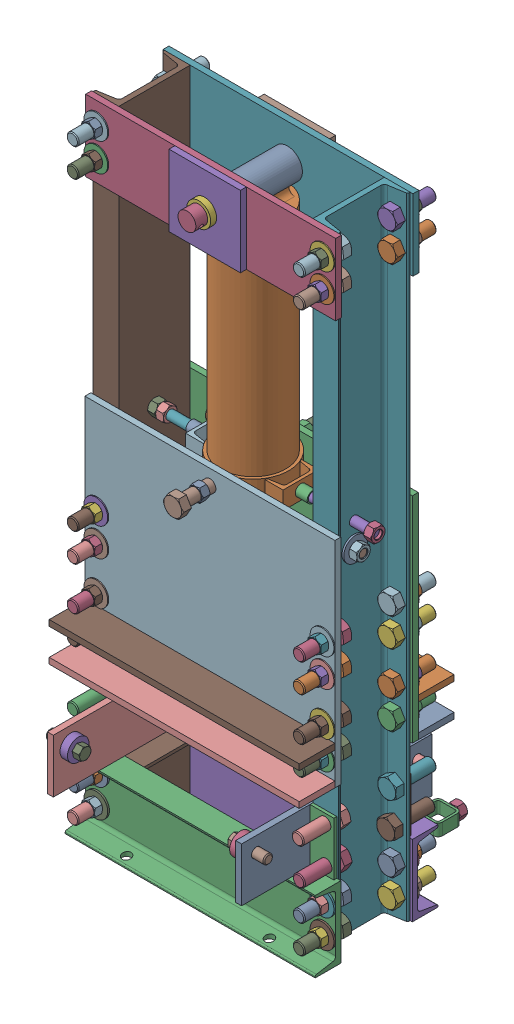
SolidWorks assembly 01-019-00-0_test, configuration Default. Lengths in mm.
Overall size (539.46 1346.2 428.04).
203 component instances, 34 part files, 0 mates.
Components (placement in the parent):
- 01-016-00-0-1: 01-016-00-0 [Default] at (0 -330.2 0) size (533.4 153.99 122.48)
  - 01-005-00-0-8-1: 01-005-00-0-8 [Default] at (-215.9 63.5 -27.3939) x (0 0 -1) z (0 1 0) size (67.69 50.8 28.57)
    - tube square_ai(PreviewCfg)-1: tube square_ai(PreviewCfg) [Default] at origin size (50.8 50.8 25.4)
    - hex nut_ai(HNUT 0.7500-10-D-C)-1: hex nut_ai(HNUT 0.7500-10-D-C) [Default] at (67.691 31.75 0) x (0 0 -1) z (1 0 0) size (28.57 33 16.89)
  - 01-005-00-0-9-1: 01-005-00-0-9 [Default] at (215.9 63.5 -27.3939) x (0 0 -1) z (0 -1 0) size (67.69 50.8 28.57)
    - tube square_ai(PreviewCfg)-1: tube square_ai(PreviewCfg) [Default] at origin size (50.8 50.8 25.4)
    - hex nut_ai(HNUT 0.7500-10-D-C)-1: hex nut_ai(HNUT 0.7500-10-D-C) [Default] at (67.691 31.75 0) x (0 0 -1) z (1 0 0) size (28.57 33 16.89)
  - 01-014-00-0-1: 01-014-00-0 [Default] at origin size (533.4 152.4 54.79)
- 01-116-00-0-1: 01-116-00-0 [Default] at (234.5817 266.7 103.5939) x (0 -1 0) z (-1 0 0) size (1346.2 152.4 109.58)
  - hex nut_ai(HNUT 0.7500-10-D-C)-1: hex nut_ai(HNUT 0.7500-10-D-C) [Default] at (-82.55 0 44.2849) size (28.57 33 16.89)
  - 01-115-00-0-1: 01-115-00-0 [Default] at origin size (1346.2 152.4 54.79)
  - 01-034-00-0-1: 01-034-00-0 [Default] at (177.8 0 54.7878) size (330.2 152.4 54.79)
- 01-114-00-0-1: 01-114-00-0 [Default] at (-234.5817 266.7 103.5939) x (0 -1 0) z (1 0 0) size (1346.2 152.4 109.58)
  - hex nut_ai(HNUT 0.7500-10-D-C)-1: hex nut_ai(HNUT 0.7500-10-D-C) [Default] at (-82.55 0 44.2849) size (28.57 33 16.89)
  - 01-034-00-0-1: 01-034-00-0 [Default] at (177.8 0 54.7878) size (330.2 152.4 54.79)
  - 01-015-00-0-1: 01-015-00-0 [Default] at origin size (1346.2 152.4 54.79)
- 01-039-00-0-1: 01-039-00-0 [Default] at (1.1707 831.85 101.4818) x (-1 0 0) z (0 0 1) size (254 946.15 152.4)
  - hex nut_ai(HNUT 0.7500-10-D-C)-1: hex nut_ai(HNUT 0.7500-10-D-C) [Default] at (-112.7125 840.359 -42.5511) x (1 0 0) z (0 -1 0) size (28.57 33 16.89)
  - PMC-21012-1: PMC-21012 [Default] at origin size (158.75 946.15 152.4)
  - 01-035-00-0-1: 01-035-00-0 [Default] at (-127 857.25 50.8) size (254 25.4 101.6)
  - 01-040-00-0-1: 01-040-00-0 [Default] at (57.15 831.85 -31.75) x (0 0 1) z (-1 0 0) size (63.5 25.4 25.4)
  - 01-040-00-0-2: 01-040-00-0 [Default] at (-57.15 831.85 31.75) x (0 0 -1) z (1 0 0) size (63.5 25.4 25.4)
  - 01-120-00-0-1: 01-120-00-0 [Default] at (-44.45 850.9 0) x (0 -1 0) z (0 0 1) size (38.1 88.9 38.1)
- 01-038-00-0-1: 01-038-00-0 [Default] at (-151.2293 -76.2 177.6818) size (304.8 82.55 152.4)
  - 01-036-00-0-1: 01-036-00-0 [Default] at origin size (304.8 25.4 152.4)
  - 01-037-00-0-1: 01-037-00-0 [Default] at (50.8 19.05 -76.2) size (19.05 63.5 19.05)
  - 01-037-00-0-2: 01-037-00-0 [Default] at (254 19.05 -76.2) size (19.05 63.5 19.05)
- 01-094-00-0-1: 01-094-00-0 [Default] at (133.1026 329.0672 91.7471) x (0 0 1) z (0 1 0) size (26.02 26.02 393.7)
  - 01-093-00-0-1: 01-093-00-0 [Default] at (-45.5164 -22.3944 39.2328) size (25.4 6.35 355.6)
  - TROD 0.7500-1x1.25-1: TROD 0.7500-1x1.25 [Default] at (-32.8164 -19.2194 -316.3672) x (0.5 -0.866025 0) z (0.866025 0.5 0) size (19.05 38.1 19.05)
- 01-113-00-0-1: 01-113-00-0 [Default] at (13.2518 299.9526 106.2418) x (1 0 0) z (0 1 0) size (63.45 76.2 38.1)
  - 01-112-00-0-1: 01-112-00-0 [Default] at (-117.0124 -34.5535 49.2974) size (38.05 76.2 38.1)
  - 01-111-00-0-1: 01-111-00-0 [Default] at (-142.4124 3.5465 49.2974) x (0 -1 0) z (0 0 1) size (23.81 25.4 23.81)
- 01-113-00-0-1-1: 01-113-00-0-1 [Default] at (-11.561 398.5474 107.4325) x (-1 0 0) z (0 -1 0) size (63.45 76.2 38.1)
  - 01-112-00-0-1: 01-112-00-0 [Default] at (-117.0124 -34.5535 49.2974) size (38.05 76.2 38.1)
  - 01-111-00-0-1: 01-111-00-0 [Default] at (-142.4124 3.5465 49.2974) x (0 -1 0) z (0 0 1) size (23.81 25.4 23.81)
- 01-117-00-0-1: 01-117-00-0 [Default] at (105.4514 349.25 103.5939) x (0 -1 0) z (0 0 1) size (28.57 165.1 33)
  - hex nut_ai(HNUT 0.7500-10-D-C)-1: hex nut_ai(HNUT 0.7500-10-D-C) [Default] at (0 165.1 0) x (1 0 0) z (0 1 0) size (28.57 33 16.89)
  - TROD 0.7500-1x6.25-1: TROD 0.7500-1x6.25 [Default] at origin size (19.05 158.75 19.05)
- 01-117-00-0-1-1: 01-117-00-0-1 [Default] at (-103.7607 349.25 103.5939) x (0 1 0) z (0 0 1) size (28.57 165.1 33)
  - hex nut_ai(HNUT 0.7500-10-D-C)-1: hex nut_ai(HNUT 0.7500-10-D-C) [Default] at (0 165.1 0) x (1 0 0) z (0 1 0) size (28.57 33 16.89)
  - TROD 0.7500-1x6.25-1: TROD 0.7500-1x6.25 [Default] at origin size (19.05 158.75 19.05)
- 01-097-00-0-1: 01-097-00-0 [Default] at (237.3376 298.45 103.5939) x (0 -0.797124 0.603815) z (0 -0.603815 -0.797124) size (141.46 99.52 78.97)
  - TROD 0.7500-1x3.5-1: TROD 0.7500-1x3.5 [Default] at origin size (19.05 88.9 19.05)
  - 01-096-00-0-1: 01-096-00-0 [Default] at (-127.635 93.6625 -64.2073) x (0.119593 0.96382 -0.238218) z (0.432432 -0.266552 -0.861367) size (9.53 152.4 9.53)
- Cam_Support_Ass-1: Cam_Support_Ass [Default] at (-231.8482 -246.6552 110.6361) x (0 0 -1) z (0 1 0) size (406.4 63.5 114.3)
  - 01-020-00-0-1: 01-020-00-0 [Default] at (-221.5578 -37.3604 106.9552) size (406.4 12.7 114.3)
  - Cam Support Tab-1: Cam Support Tab [Default] at (83.2422 -24.6604 106.9552) x (0 1 0) z (-1 0 0) size (50.8 114.3 6.35)
  - Cam Support Tab-2: Cam Support Tab [Default] at (-75.5078 -24.6604 106.9552) x (0 1 0) z (-1 0 0) size (50.8 114.3 6.35)
- Cam_Support_Ass_3-1: Cam_Support_Ass_3 [Default] at (205.4753 -251.743 123.9765) x (0 0 1) z (0 1 0) size (406.4 63.5 114.3)
  - 01-020-00-0-1: 01-020-00-0 [Default] at (-198.1826 -10.9875 112.043) size (406.4 12.7 114.3)
  - Cam Support Tab-1: Cam Support Tab [Default] at (-102.9326 1.7125 112.043) x (0 1 0) z (-1 0 0) size (50.8 114.3 6.35)
  - Cam Support Tab-2: Cam Support Tab [Default] at (55.8174 1.7125 112.043) x (0 1 0) z (-1 0 0) size (50.8 114.3 6.35)
- Base Plate Ass-1: Base Plate Ass [Default] at (51.7384 868.2539 156.4809) size (533.4 152.4 38.1)
  - Base plate update-1: Base plate update [Default] at (-316.9216 -80.8539 23.313) size (533.4 152.4 12.7)
  - Base Plate Support-1: Base Plate Support [Default] at (-126.4216 -80.8539 36.013) size (152.4 152.4 12.7)
  - 01-109-00-0-1: 01-109-00-0 [Default] at (-50.2216 -4.6539 23.313) x (1 0 0) z (0 -1 0) size (50.8 38.1 50.8)
- Base Plate Ass-1-1: Base Plate Ass-1 [Default] at (-48.7992 868.2539 50.7069) x (-1 0 0) z (0 0 -1) size (533.4 152.4 38.1)
  - Base plate update-1: Base plate update [Default] at (-316.9216 -80.8539 23.313) size (533.4 152.4 12.7)
  - Base Plate Support-1: Base Plate Support [Default] at (-126.4216 -80.8539 36.013) size (152.4 152.4 12.7)
  - 01-109-00-0-1: 01-109-00-0 [Default] at (-50.2216 -4.6539 23.313) x (1 0 0) z (0 -1 0) size (50.8 38.1 50.8)
- chamber wall ass-1: chamber wall ass [Default] at (-124.178 118.8769 136.5221) x (-1 0 0) z (0 0 1) size (533.4 457.2 88.9)
  - Chamber wall flange-1: Chamber wall flange [Default] at (-328.7125 182.3769 97.008) size (533.4 12.7 76.2)
  - Chamber wall flange-2: Chamber wall flange [Default] at (-328.7125 112.5269 97.008) size (533.4 12.7 76.2)
  - Chamber Walls-1: Chamber Walls [Default] at (-390.878 195.0769 43.2718) size (533.4 457.2 12.7)
- chamber wall ass-1-1: chamber wall ass-1 [Default] at (124.178 118.8769 70.6657) x (1 0 0) z (0 0 -1) size (533.4 457.2 88.9)
  - Chamber wall flange-1: Chamber wall flange [Default] at (-328.7125 182.3769 97.008) size (533.4 12.7 76.2)
  - Chamber wall flange-2: Chamber wall flange [Default] at (-328.7125 112.5269 97.008) size (533.4 12.7 76.2)
  - Chamber Walls-1: Chamber Walls [Default] at (-390.878 195.0769 43.2718) size (533.4 457.2 12.7)
- hex nut_ai(HNUT 0.7500-10-D-C)-1: hex nut_ai(HNUT 0.7500-10-D-C) [Default] at (-241.3 30.1625 12.5315) x (-0.923728 0.383049 0) z (0 0 1) size (28.57 33 16.89)
- hex nut_ai(HNUT 0.7500-10-D-C)-2: hex nut_ai(HNUT 0.7500-10-D-C) [Default] at (241.3 833.4375 211.5439) size (28.57 33 16.89)
- hex nut_ai(HNUT 0.7500-10-D-C)-3: hex nut_ai(HNUT 0.7500-10-D-C) [Default] at (241.3 -360.3625 211.5439) size (28.57 33 16.89)
- hex nut_ai(HNUT 0.7500-10-D-C)-4: hex nut_ai(HNUT 0.7500-10-D-C) [Default] at (173.4058 349.25 103.5939) x (0 0 1) z (-1 0 0) size (28.57 33 16.89)
- hex nut_ai(HNUT 0.7500-10-D-C)-5: hex nut_ai(HNUT 0.7500-10-D-C) [Default] at (-241.3 -30.1625 194.6563) x (-1 0 0) z (0 0 -1) size (28.57 33 16.89)
- hex nut_ai(HNUT 0.7500-10-D-C)-6: hex nut_ai(HNUT 0.7500-10-D-C) [Default] at (241.3 893.7625 211.5439) size (28.57 33 16.89)
- hex nut_ai(HNUT 0.7500-10-D-C)-7: hex nut_ai(HNUT 0.7500-10-D-C) [Default] at (241.3 -300.0375 211.5439) size (28.57 33 16.89)
- hex nut_ai(HNUT 0.7500-10-D-C)-8: hex nut_ai(HNUT 0.7500-10-D-C) [Default] at (-241.3 30.1625 194.6563) x (-1 0 0) z (0 0 -1) size (28.57 33 16.89)
- hex nut_ai(HNUT 0.7500-10-D-C)-9: hex nut_ai(HNUT 0.7500-10-D-C) [Default] at (241.3 122.2375 -4.3561) x (0.923728 0.383049 0) z (0 0 -1) size (28.57 33 16.89)
- hex nut_ai(HNUT 0.7500-10-D-C)-10: hex nut_ai(HNUT 0.7500-10-D-C) [Default] at (0 349.25 207.0227) x (0 1 0) z (0 0 -1) size (28.57 33 16.89)
- hex nut_ai(HNUT 0.7500-10-D-C)-11: hex nut_ai(HNUT 0.7500-10-D-C) [Default] at (241.3 182.5625 -4.3561) x (0.923728 0.383049 0) z (0 0 -1) size (28.57 33 16.89)
- hex nut_ai(HNUT 0.7500-10-D-C)-12: hex nut_ai(HNUT 0.7500-10-D-C) [Default] at (0 349.25 0.1651) x (0.924225 -0.381849 0) z (0 0 1) size (28.57 33 16.89)
- hex nut_ai(HNUT 0.7500-10-D-C)-13: hex nut_ai(HNUT 0.7500-10-D-C) [Default] at (-241.3 122.2375 194.6563) x (-1 0 0) z (0 0 -1) size (28.57 33 16.89)
- hex nut_ai(HNUT 0.7500-10-D-C)-14: hex nut_ai(HNUT 0.7500-10-D-C) [Default] at (-100.4293 -8.509 101.4818) x (1 0 0) z (0 1 0) size (28.57 33 16.89)
- hex nut_ai(HNUT 0.7500-10-D-C)-15: hex nut_ai(HNUT 0.7500-10-D-C) [Default] at (-241.3 182.5625 194.6563) x (-1 0 0) z (0 0 -1) size (28.57 33 16.89)
- hex nut_ai(HNUT 0.7500-10-D-C)-16: hex nut_ai(HNUT 0.7500-10-D-C) [Default] at (-241.3 -360.3625 -4.3527) x (-1 0 0) z (0 0 -1) size (28.57 33 16.89)
- hex nut_ai(HNUT 0.7500-10-D-C)-17: hex nut_ai(HNUT 0.7500-10-D-C) [Default] at (241.3 833.4375 -4.3561) x (0.923728 0.383049 0) z (0 0 -1) size (28.57 33 16.89)
- hex nut_ai(HNUT 0.7500-10-D-C)-18: hex nut_ai(HNUT 0.7500-10-D-C) [Default] at (241.3 893.7625 -4.3561) x (0.923728 0.383049 0) z (0 0 -1) size (28.57 33 16.89)
- hex nut_ai(HNUT 0.7500-10-D-C)-19: hex nut_ai(HNUT 0.7500-10-D-C) [Default] at (-173.4058 349.25 103.5939) x (0 0 -1) z (1 0 0) size (28.57 33 16.89)
- hex nut_ai(HNUT 0.7500-10-D-C)-20: hex nut_ai(HNUT 0.7500-10-D-C) [Default] at (-241.3 833.4375 194.6563) x (-1 0 0) z (0 0 -1) size (28.57 33 16.89)
- hex nut_ai(HNUT 0.7500-10-D-C)-21: hex nut_ai(HNUT 0.7500-10-D-C) [Default] at (-241.3 -360.3625 194.6563) x (-1 0 0) z (0 0 -1) size (28.57 33 16.89)
- hex nut_ai(HNUT 0.7500-10-D-C)-22: hex nut_ai(HNUT 0.7500-10-D-C) [Default] at (-241.3 893.7625 194.6563) x (-1 0 0) z (0 0 -1) size (28.57 33 16.89)
- hex nut_ai(HNUT 0.7500-10-D-C)-23: hex nut_ai(HNUT 0.7500-10-D-C) [Default] at (-241.3 -300.0375 194.6563) x (-1 0 0) z (0 0 -1) size (28.57 33 16.89)
- hex nut_ai(HNUT 0.7500-10-D-C)-24: hex nut_ai(HNUT 0.7500-10-D-C) [Default] at (241.3 -30.1625 -4.3561) x (0.923728 0.383049 0) z (0 0 -1) size (28.57 33 16.89)
- hex nut_ai(HNUT 0.7500-10-D-C)-25: hex nut_ai(HNUT 0.7500-10-D-C) [Default] at (-241.3 122.2375 12.5315) x (-0.923728 0.383049 0) z (0 0 1) size (28.57 33 16.89)
- hex nut_ai(HNUT 0.7500-10-D-C)-26: hex nut_ai(HNUT 0.7500-10-D-C) [Default] at (241.3 30.1625 -4.3561) x (0.923728 0.383049 0) z (0 0 -1) size (28.57 33 16.89)
- hex nut_ai(HNUT 0.7500-10-D-C)-27: hex nut_ai(HNUT 0.7500-10-D-C) [Default] at (-241.3 182.5625 12.5315) x (-0.923728 0.383049 0) z (0 0 1) size (28.57 33 16.89)
- hex nut_ai(HNUT 0.7500-10-D-C)-28: hex nut_ai(HNUT 0.7500-10-D-C) [Default] at (241.3 -30.1625 211.5439) size (28.57 33 16.89)
- hex nut_ai(HNUT 0.7500-10-D-C)-29: hex nut_ai(HNUT 0.7500-10-D-C) [Default] at (203.4286 298.45 103.5939) x (0 0 -1) z (1 0 0) size (28.57 33 16.89)
- hex nut_ai(HNUT 0.7500-10-D-C)-30: hex nut_ai(HNUT 0.7500-10-D-C) [Default] at (-241.3 833.4375 12.5315) x (-0.923728 0.383049 0) z (0 0 1) size (28.57 33 16.89)
- hex nut_ai(HNUT 0.7500-10-D-C)-31: hex nut_ai(HNUT 0.7500-10-D-C) [Default] at (-241.3 -300.0375 -4.3527) x (-0.998531 -0.05419 0) z (0 0 -1) size (28.57 33 16.89)
- hex nut_ai(HNUT 0.7500-10-D-C)-32: hex nut_ai(HNUT 0.7500-10-D-C) [Default] at (241.3 30.1625 211.5439) size (28.57 33 16.89)
- hex nut_ai(HNUT 0.7500-10-D-C)-33: hex nut_ai(HNUT 0.7500-10-D-C) [Default] at (238.9378 298.45 103.5939) x (0 0 -1) z (1 0 0) size (28.57 33 16.89)
- hex nut_ai(HNUT 0.7500-10-D-C)-34: hex nut_ai(HNUT 0.7500-10-D-C) [Default] at (-241.3 893.7625 12.5315) x (-0.923728 0.383049 0) z (0 0 1) size (28.57 33 16.89)
- hex nut_ai(HNUT 0.7500-10-D-C)-35: hex nut_ai(HNUT 0.7500-10-D-C) [Default] at (241.3 -300.0375 12.5349) x (0.998531 -0.05419 0) z (0 0 1) size (28.57 33 16.89)
- hex nut_ai(HNUT 0.7500-10-D-C)-36: hex nut_ai(HNUT 0.7500-10-D-C) [Default] at (113.8832 8.382 58.9307) x (1 0 0) z (0 1 0) size (28.57 33 16.89)
- hex nut_ai(HNUT 0.7500-10-D-C)-37: hex nut_ai(HNUT 0.7500-10-D-C) [Default] at (102.7707 -8.509 101.4818) x (1 0 0) z (0 1 0) size (28.57 33 16.89)
- hex nut_ai(HNUT 0.7500-10-D-C)-38: hex nut_ai(HNUT 0.7500-10-D-C) [Default] at (241.3 122.2375 211.5439) size (28.57 33 16.89)
- hex nut_ai(HNUT 0.7500-10-D-C)-39: hex nut_ai(HNUT 0.7500-10-D-C) [Default] at (-241.3 -30.1625 12.5315) x (-0.923728 0.383049 0) z (0 0 1) size (28.57 33 16.89)
- hex nut_ai(HNUT 0.7500-10-D-C)-40: hex nut_ai(HNUT 0.7500-10-D-C) [Default] at (241.3 182.5625 211.5439) size (28.57 33 16.89)
- hex nut_ai(HNUT 0.7500-10-D-C)-41: hex nut_ai(HNUT 0.7500-10-D-C) [Default] at (241.3 -360.3625 12.5349) size (28.57 33 16.89)
- hex bolt_ai(PreviewCfg)-1: hex bolt_ai(PreviewCfg) [Default] at (-241.3 833.4375 150.722) x (0 0 1) z (-0.381849 0.924225 0) size (93.98 43.99 38.1)
- hex bolt_ai(PreviewCfg)-2: hex bolt_ai(PreviewCfg) [Default] at (-241.3 -360.3625 150.722) x (0 0 1) z (-0.381849 0.924225 0) size (93.98 43.99 38.1)
- hex bolt_ai(PreviewCfg)-3: hex bolt_ai(PreviewCfg) [Default] at (238.9378 -234.95 56.4658) x (0 0 -1) z (1 0 0) size (93.98 43.99 38.1)
- hex bolt_ai(PreviewCfg)-4: hex bolt_ai(PreviewCfg) [Default] at (-241.3 893.7625 150.722) x (0 0 1) z (-0.381849 0.924225 0) size (93.98 43.99 38.1)
- hex bolt_ai(PreviewCfg)-5: hex bolt_ai(PreviewCfg) [Default] at (-241.3 -300.0375 150.722) x (0 0 1) z (-0.381849 0.924225 0) size (93.98 43.99 38.1)
- hex bolt_ai(PreviewCfg)-6: hex bolt_ai(PreviewCfg) [Default] at (-241.3 30.1625 56.4658) x (0 0 -1) z (0 -1 0) size (93.98 43.99 38.1)
- hex bolt_ai(PreviewCfg)-7: hex bolt_ai(PreviewCfg) [Default] at (241.3 -30.1625 56.4658) x (0 0 -1) z (0 1 0) size (93.98 43.99 38.1)
- hex bolt_ai(PreviewCfg)-8: hex bolt_ai(PreviewCfg) [Default] at (241.3191 -234.95 150.722) x (0 0 1) z (-0.001298 0.999999 0) size (93.98 43.99 38.1)
- hex bolt_ai(PreviewCfg)-9: hex bolt_ai(PreviewCfg) [Default] at (-241.3 122.2375 56.4658) x (0 0 -1) z (0 -1 0) size (93.98 43.99 38.1)
- hex bolt_ai(PreviewCfg)-10: hex bolt_ai(PreviewCfg) [Default] at (-241.3191 -234.95 150.722) x (0 0 1) z (-1 0 0) size (93.98 43.99 38.1)
- hex bolt_ai(PreviewCfg)-11: hex bolt_ai(PreviewCfg) [Default] at (-241.3191 -234.95 56.4658) x (0 0 -1) z (-0.923728 -0.383049 0) size (93.98 43.99 38.1)
- hex bolt_ai(PreviewCfg)-12: hex bolt_ai(PreviewCfg) [Default] at (-241.3 -300.0375 56.4658) x (0 0 -1) z (0 -1 0) size (93.98 43.99 38.1)
- hex bolt_ai(PreviewCfg)-13: hex bolt_ai(PreviewCfg) [Default] at (241.3 -30.1625 150.722) x (0 0 1) z (-0.381849 -0.924225 0) size (93.98 43.99 38.1)
- hex bolt_ai(PreviewCfg)-14: hex bolt_ai(PreviewCfg) [Default] at (-241.3 833.4375 56.4658) x (0 0 -1) z (0 -1 0) size (93.98 43.99 38.1)
- hex bolt_ai(PreviewCfg)-15: hex bolt_ai(PreviewCfg) [Default] at (241.3 30.1625 150.722) x (0 0 1) z (-0.381849 -0.924225 0) size (93.98 43.99 38.1)
- hex bolt_ai(PreviewCfg)-16: hex bolt_ai(PreviewCfg) [Default] at (241.3 182.5625 56.4658) x (0 0 -1) z (0 1 0) size (93.98 43.99 38.1)
- hex bolt_ai(PreviewCfg)-17: hex bolt_ai(PreviewCfg) [Default] at (241.3 -300.0375 56.4658) x (0 0 -1) z (0 1 0) size (93.98 43.99 38.1)
- hex bolt_ai(PreviewCfg)-18: hex bolt_ai(PreviewCfg) [Default] at (241.3 122.2375 150.722) x (0 0 1) z (-0.381849 -0.924225 0) size (93.98 43.99 38.1)
- hex bolt_ai(PreviewCfg)-19: hex bolt_ai(PreviewCfg) [Default] at (-241.3 -30.1625 56.4658) x (0 0 -1) z (0 -1 0) size (93.98 43.99 38.1)
- hex bolt_ai(PreviewCfg)-20: hex bolt_ai(PreviewCfg) [Default] at (241.3 182.5625 150.722) x (0 0 1) z (-0.381849 -0.924225 0) size (93.98 43.99 38.1)
- hex bolt_ai(PreviewCfg)-21: hex bolt_ai(PreviewCfg) [Default] at (241.3 893.7625 56.4658) x (0 0 -1) z (0 1 0) size (93.98 43.99 38.1)
- hex bolt_ai(PreviewCfg)-22: hex bolt_ai(PreviewCfg) [Default] at (241.3 -360.3625 56.4658) x (0 0 -1) z (0.005072 0.999987 0) size (93.98 43.99 38.1)
- hex bolt_ai(PreviewCfg)-23: hex bolt_ai(PreviewCfg) [Default] at (241.3191 -158.75 56.4658) x (0 0 -1) z (1 0 0) size (93.98 43.99 38.1)
- hex bolt_ai(PreviewCfg)-24: hex bolt_ai(PreviewCfg) [Default] at (241.3 833.4375 150.722) x (0 0 1) z (-0.381849 -0.924225 0) size (93.98 43.99 38.1)
- hex bolt_ai(PreviewCfg)-25: hex bolt_ai(PreviewCfg) [Default] at (241.3 -360.3625 150.722) x (0 0 1) z (-0.381849 -0.924225 0) size (93.98 43.99 38.1)
- hex bolt_ai(PreviewCfg)-26: hex bolt_ai(PreviewCfg) [Default] at (238.9378 -158.75 150.722) x (0 0 1) z (-0.923728 -0.383049 0) size (93.98 43.99 38.1)
- hex bolt_ai(PreviewCfg)-27: hex bolt_ai(PreviewCfg) [Default] at (-241.3 -30.1625 150.722) x (0 0 1) z (-0.381849 0.924225 0) size (93.98 43.99 38.1)
- hex bolt_ai(PreviewCfg)-28: hex bolt_ai(PreviewCfg) [Default] at (241.3 893.7625 150.722) x (0 0 1) z (-0.381849 -0.924225 0) size (93.98 43.99 38.1)
- hex bolt_ai(PreviewCfg)-29: hex bolt_ai(PreviewCfg) [Default] at (241.3 -300.0375 150.722) x (0 0 1) z (-0.381849 -0.924225 0) size (93.98 43.99 38.1)
- hex bolt_ai(PreviewCfg)-30: hex bolt_ai(PreviewCfg) [Default] at (241.3 30.1625 56.4658) x (0 0 -1) z (0 1 0) size (93.98 43.99 38.1)
- hex bolt_ai(PreviewCfg)-31: hex bolt_ai(PreviewCfg) [Default] at (-241.3191 -158.75 150.722) x (0 0 1) z (-1 0 0) size (93.98 43.99 38.1)
- hex bolt_ai(PreviewCfg)-32: hex bolt_ai(PreviewCfg) [Default] at (-241.3 30.1625 150.722) x (0 0 1) z (-0.381849 0.924225 0) size (93.98 43.99 38.1)
- hex bolt_ai(PreviewCfg)-33: hex bolt_ai(PreviewCfg) [Default] at (-241.3 182.5625 56.4658) x (0 0 -1) z (0 -1 0) size (93.98 43.99 38.1)
- hex bolt_ai(PreviewCfg)-34: hex bolt_ai(PreviewCfg) [Default] at (241.3 122.2375 56.4658) x (0 0 -1) z (0 1 0) size (93.98 43.99 38.1)
- hex bolt_ai(PreviewCfg)-35: hex bolt_ai(PreviewCfg) [Default] at (-241.3191 -158.75 56.4658) x (0 0 -1) z (-0.923728 -0.383049 0) size (93.98 43.99 38.1)
- hex bolt_ai(PreviewCfg)-36: hex bolt_ai(PreviewCfg) [Default] at (0 349.25 271.6618) x (0 0 -1) z (0 -1 0) size (93.98 43.99 38.1)
- hex bolt_ai(PreviewCfg)-37: hex bolt_ai(PreviewCfg) [Default] at (0 349.25 -68.6982) x (0 0 1) z (-0.924225 0.381849 0) size (93.98 43.99 38.1)
- hex bolt_ai(PreviewCfg)-38: hex bolt_ai(PreviewCfg) [Default] at (-241.3 122.2375 150.722) x (0 0 1) z (-0.381849 0.924225 0) size (93.98 43.99 38.1)
- hex bolt_ai(PreviewCfg)-39: hex bolt_ai(PreviewCfg) [Default] at (-241.3 182.5625 150.722) x (0 0 1) z (-0.381849 0.924225 0) size (93.98 43.99 38.1)
- hex bolt_ai(PreviewCfg)-40: hex bolt_ai(PreviewCfg) [Default] at (-241.3 893.7625 56.4658) x (0 0 -1) z (0 -1 0) size (93.98 43.99 38.1)
- hex bolt_ai(PreviewCfg)-41: hex bolt_ai(PreviewCfg) [Default] at (-241.3 -360.3625 56.4658) x (0 0 -1) z (0.005072 -0.999987 0) size (93.98 43.99 38.1)
- hex bolt_ai(PreviewCfg)-42: hex bolt_ai(PreviewCfg) [Default] at (241.3 833.4375 56.4658) x (0 0 -1) z (0 1 0) size (93.98 43.99 38.1)
- 01-014-00-0-1: 01-014-00-0 [Default] at (0 -330.2 207.1878) x (-1 0 0) z (0 0 -1) size (533.4 152.4 54.79)
- RM3-2RS-1: RM3-2RS [Default] at (173.0078 -171.45 300.4439) x (1 0 0) z (0 -0.000451 1) size (15.88 46.04 46.04)
- RM3-2RS-2: RM3-2RS [Default] at (-173.0078 -171.45 300.4439) x (-1 0 0) z (0 0.668301 -0.743891) size (15.88 46.04 46.04)
- RM3-2RS-3: RM3-2RS [Default] at (-173.0078 -171.45 -42.4561) x (-1 0 0) z (0 0.924397 0.381433) size (15.88 46.04 46.04)
- RM3-2RS-4: RM3-2RS [Default] at (173.0078 -171.45 -42.4561) x (1 0 0) z (0 -0.000451 1) size (15.88 46.04 46.04)
- hex bolt_am_Smaller(PreviewCfg)-1: hex bolt_am_Smaller(PreviewCfg) [Default] at (158.0078 -171.45 300.4439) size (75 27.71 24)
- hex bolt_am_Smaller(PreviewCfg)-2: hex bolt_am_Smaller(PreviewCfg) [Default] at (-158.0078 -171.45 300.4439) x (-1 0 0) z (0 -0.23868 0.971098) size (75 27.71 24)
- hex bolt_am_Smaller(PreviewCfg)-3: hex bolt_am_Smaller(PreviewCfg) [Default] at (158.0078 -171.45 -42.4561) size (75 27.71 24)
- hex bolt_am_Smaller(PreviewCfg)-4: hex bolt_am_Smaller(PreviewCfg) [Default] at (-158.0078 -171.45 -42.4561) x (-1 0 0) z (0 0.924225 0.381849) size (75 27.71 24)
- WASHER 0.7500-WIDE-1: WASHER 0.7500-WIDE [Default] at (241.3 182.5625 190.8937) size (50.8 50.8 3.76)
- WASHER 0.7500-WIDE-2: WASHER 0.7500-WIDE [Default] at (241.3 833.4375 12.5349) size (50.8 50.8 3.76)
- WASHER 0.7500-WIDE-3: WASHER 0.7500-WIDE [Default] at (241.3 -30.1625 12.5349) size (50.8 50.8 3.76)
- WASHER 0.7500-WIDE-4: WASHER 0.7500-WIDE [Default] at (-241.3 833.4375 194.6529) x (-1 0 0) z (0 0 -1) size (50.8 50.8 3.76)
- WASHER 0.7500-WIDE-5: WASHER 0.7500-WIDE [Default] at (241.3 30.1625 12.5349) size (50.8 50.8 3.76)
- WASHER 0.7500-WIDE-6: WASHER 0.7500-WIDE [Default] at (-241.3 182.5625 16.2941) x (-1 0 0) z (0 0 -1) size (50.8 50.8 3.76)
- WASHER 0.7500-WIDE-7: WASHER 0.7500-WIDE [Default] at (241.3 893.7625 190.8937) size (50.8 50.8 3.76)
- WASHER 0.7500-WIDE-8: WASHER 0.7500-WIDE [Default] at (241.3 -300.0375 190.8937) size (50.8 50.8 3.76)
- WASHER 0.7500-WIDE-9: WASHER 0.7500-WIDE [Default] at (-241.3 30.1625 194.6529) x (-1 0 0) z (0 0 -1) size (50.8 50.8 3.76)
- WASHER 0.7500-WIDE-10: WASHER 0.7500-WIDE [Default] at (-241.3 122.2375 16.2941) x (-1 0 0) z (0 0 -1) size (50.8 50.8 3.76)
- WASHER 0.7500-WIDE-11: WASHER 0.7500-WIDE [Default] at (-241.3191 -234.95 186.1439) size (50.8 50.8 3.76)
- WASHER 0.7500-WIDE-12: WASHER 0.7500-WIDE [Default] at (203.4286 298.45 103.5939) x (0 0 -1) z (1 0 0) size (50.8 50.8 3.76)
- WASHER 0.7500-WIDE-13: WASHER 0.7500-WIDE [Default] at (-241.3 -300.0375 16.2941) x (-1 0 0) z (0 0 -1) size (50.8 50.8 3.76)
- WASHER 0.7500-WIDE-14: WASHER 0.7500-WIDE [Default] at (222.0468 298.45 103.5939) x (0 0 -1) z (-1 0 0) size (50.8 50.8 3.76)
- WASHER 0.7500-WIDE-15: WASHER 0.7500-WIDE [Default] at (-241.3 893.7625 16.2941) x (-1 0 0) z (0 0 -1) size (50.8 50.8 3.76)
- WASHER 0.7500-WIDE-16: WASHER 0.7500-WIDE [Default] at (241.3 -30.1625 190.8937) size (50.8 50.8 3.76)
- WASHER 0.7500-WIDE-17: WASHER 0.7500-WIDE [Default] at (241.3 -300.0375 12.5349) size (50.8 50.8 3.76)
- WASHER 0.7500-WIDE-18: WASHER 0.7500-WIDE [Default] at (-241.3 182.5625 194.6529) x (-1 0 0) z (0 0 -1) size (50.8 50.8 3.76)
- WASHER 0.7500-WIDE-19: WASHER 0.7500-WIDE [Default] at (-241.3 833.4375 16.2941) x (-1 0 0) z (0 0 -1) size (50.8 50.8 3.76)
- WASHER 0.7500-WIDE-20: WASHER 0.7500-WIDE [Default] at (-241.3 -30.1625 16.2941) x (-1 0 0) z (0 0 -1) size (50.8 50.8 3.76)
- WASHER 0.7500-WIDE-21: WASHER 0.7500-WIDE [Default] at (241.3 -360.3625 12.5349) size (50.8 50.8 3.76)
- WASHER 0.7500-WIDE-22: WASHER 0.7500-WIDE [Default] at (-241.3 30.1625 16.2941) x (-1 0 0) z (0 0 -1) size (50.8 50.8 3.76)
- WASHER 0.7500-WIDE-23: WASHER 0.7500-WIDE [Default] at (241.3 122.2375 190.8937) size (50.8 50.8 3.76)
- WASHER 0.7500-WIDE-24: WASHER 0.7500-WIDE [Default] at (241.3 -360.3625 190.8937) size (50.8 50.8 3.76)
- WASHER 0.7500-WIDE-25: WASHER 0.7500-WIDE [Default] at (-241.3 893.7625 194.6529) x (-1 0 0) z (0 0 -1) size (50.8 50.8 3.76)
- WASHER 0.7500-WIDE-26: WASHER 0.7500-WIDE [Default] at (-241.3 -300.0375 194.6529) x (-1 0 0) z (0 0 -1) size (50.8 50.8 3.76)
- WASHER 0.7500-WIDE-27: WASHER 0.7500-WIDE [Default] at (241.3 833.4375 190.8937) size (50.8 50.8 3.76)
- WASHER 0.7500-WIDE-28: WASHER 0.7500-WIDE [Default] at (-241.3 -30.1625 194.6529) x (-1 0 0) z (0 0 -1) size (50.8 50.8 3.76)
- WASHER 0.7500-WIDE-29: WASHER 0.7500-WIDE [Default] at (241.3 182.5625 12.5349) size (50.8 50.8 3.76)
- WASHER 0.7500-WIDE-30: WASHER 0.7500-WIDE [Default] at (-241.3 -360.3625 16.2941) x (-1 0 0) z (0 0 -1) size (50.8 50.8 3.76)
- WASHER 0.7500-WIDE-31: WASHER 0.7500-WIDE [Default] at (241.3 30.1625 190.8937) size (50.8 50.8 3.76)
- WASHER 0.7500-WIDE-32: WASHER 0.7500-WIDE [Default] at (241.3 122.2375 12.5349) size (50.8 50.8 3.76)
- WASHER 0.7500-WIDE-33: WASHER 0.7500-WIDE [Default] at (-241.3 122.2375 194.6529) x (-1 0 0) z (0 0 -1) size (50.8 50.8 3.76)
- WASHER 0.7500-WIDE-34: WASHER 0.7500-WIDE [Default] at (-241.3 -360.3625 194.6529) x (-1 0 0) z (0 0 -1) size (50.8 50.8 3.76)
- WASHER 0.7500-WIDE-35: WASHER 0.7500-WIDE [Default] at (241.3 893.7625 12.5349) size (50.8 50.8 3.76)
- 01-107-00-0-1: 01-107-00-0 [Default] at (-207.1878 -257.175 103.5939) x (0 -1 0) z (0 0 1) size (50.8 50.8 152.4)
- 01-107-00-0-2: 01-107-00-0 [Default] at (207.1878 -257.175 103.5939) x (0 -1 0) z (0 0 -1) size (50.8 50.8 152.4)
- 01-095-00-0-1: 01-095-00-0 [Default] at (123.4082 342.9 58.9307) x (0 -0.957416 0.288712) z (-1 0 0) size (12.7 12.7 6.35)
- 01-095-00-0-2: 01-095-00-0 [Default] at (123.4082 292.1 58.9307) x (0 -0.957416 0.288712) z (-1 0 0) size (12.7 12.7 6.35)
- 01-095-00-0-3: 01-095-00-0 [Default] at (123.4082 63.5 58.9307) x (0 -0.957416 0.288712) z (-1 0 0) size (12.7 12.7 6.35)
- 01-103-00-0-1: 01-103-00-0 [Default] at (1.5168 863.6 -36.2976) x (0.402511 0.915415 0) z (0.915415 -0.402511 0) size (38.1 279.4 38.1)
- WASHER 0.375-WIDE-1: WASHER 0.375-WIDE [Default] at (194.4878 -171.45 300.4439) size (2.11 25.4 25.4)
